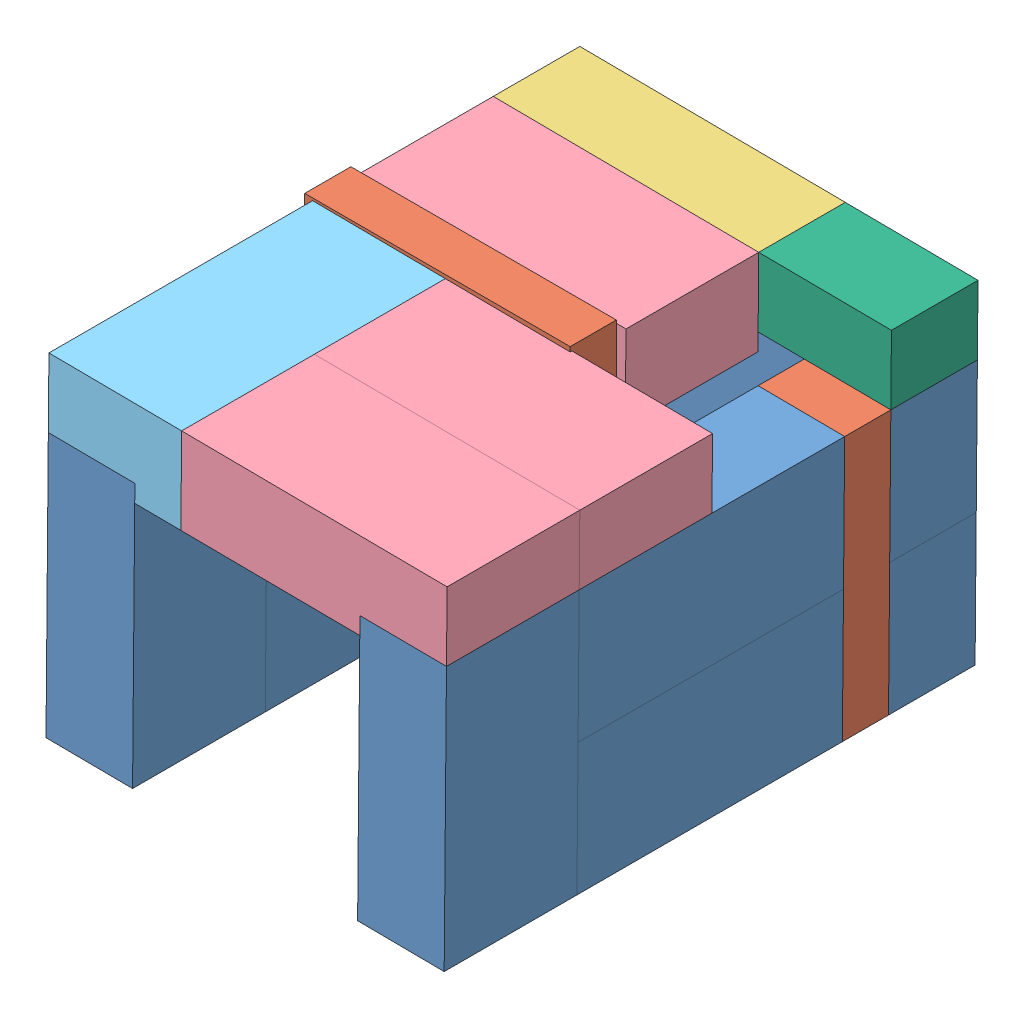
SolidWorks assembly Assem2, configuration Default. Lengths in mm.
Overall size (351.83 295.72 462.01).
21 component instances, 6 part files, 24 mates.
Components (placement in the parent):
- Side Wall ext-1: Side Wall ext [Default] at (111.7562 210.1933 441.078) size (77 230.65 385)
  - Brick-Whole-1: Brick-Whole [Default] x (-0.008727 -0.999962 0) z (0 0 1) size (230 75 115)
  - Brick-Whole-2: Brick-Whole [Default] at (0.5018 57.4978 -172.5) x (0 0 1) z (0.008727 0.999962 0) size (230 75 115)
  - Brick-Whole-3: Brick-Whole [Default] at (-0.5018 -57.4978 -172.5) x (0 0 1) z (0.008727 0.999962 0) size (230 75 115)
  - Brick-Whole-trimmed-1: Brick-Whole-trimmed [Default] at (0 0 -307.5) x (-0.008727 -0.999962 0) z (0 0 1) size (230 75 40)
- Side Wall ext-2: Side Wall ext [Default] at (381.7459 207.8371 441.078) size (77 230.65 385)
  - Brick-Whole-1: Brick-Whole [Default] x (-0.008727 -0.999962 0) z (0 0 1) size (230 75 115)
  - Brick-Whole-2: Brick-Whole [Default] at (0.5018 57.4978 -172.5) x (0 0 1) z (0.008727 0.999962 0) size (230 75 115)
  - Brick-Whole-3: Brick-Whole [Default] at (-0.5018 -57.4978 -172.5) x (0 0 1) z (0.008727 0.999962 0) size (230 75 115)
  - Brick-Whole-trimmed-1: Brick-Whole-trimmed [Default] at (0 0 -307.5) x (-0.008727 -0.999962 0) z (0 0 1) size (230 75 40)
- Side Wall-1: Side Wall [Default] at (131.7554 210.0187 76.078) x (0.000076 0.008726 0.999962) z (-0.999962 0.008727 0) size (77 230.65 345)
  - Brick-Whole-1: Brick-Whole [Default] x (-0.008727 -0.999962 0) z (0 0 1) size (230 75 115)
  - Brick-Whole-2: Brick-Whole [Default] at (0.5018 57.4978 -172.5) x (0 0 1) z (0.008727 0.999962 0) size (230 75 115)
  - Brick-Whole-3: Brick-Whole [Default] at (-0.5018 -57.4978 -172.5) x (0 0 1) z (0.008727 0.999962 0) size (230 75 115)
- Brick-Whole-70-1: Brick-Whole-70 [Default] at (190.5186 354.5114 76.078) x (0.999962 -0.008727 0) z (-0.008727 -0.999962 0) size (230 75 60)
- Brick-Sharp-BackCut-1: Brick-Sharp-BackCut [Default] at (305.4487 346.0082 441.078) x (-0.999962 0.008727 0) z (0 0 1) size (230 75 115)
- Brick-Sharp-SideCut-1: Brick-Sharp-SideCut [Default] at (132.9553 347.5135 383.578) x (0 0 1) z (0.999962 -0.008727 0) size (230 75 115)
- Brick-Sharp-BackCut-2: Brick-Sharp-BackCut [Default] at (305.4487 346.0082 326.078) x (-0.999962 0.008727 0) z (0 0 1) size (230 75 115)
- Brick-Whole-trimmed-3: Brick-Whole-trimmed [Default] at (183.9442 350.0777 250.0949) size (230 75 40)
- Brick-Sharp-BackCut-3: Brick-Sharp-BackCut [Default] at (190.4531 347.0117 171.078) x (0.999962 -0.008727 0) z (0 0 -1) size (230 75 115)
- Brick-Whole-70115-1: Brick-Whole-70115 [Default] at (363.012 353.0061 76.078) x (0.008727 0.999962 0) z (-0.999962 0.008727 0) size (60 75 115)
Mates (geometry in assembly coordinates):
- Coincident21: coincident anti-aligned: plane of Side Wall ext-1/Brick-Whole-trimmed-1 through (150.2583 324.8616 113.578) normal (0 0 -1); plane of Side Wall-1/Brick-Whole-1 through (131.7554 210.0187 113.578) normal (0 0 1)
- Coincident22: coincident aligned: plane of Side Wall ext-1/Brick-Whole-trimmed-1 through (74.2576 210.5205 133.578) normal (-0.999962 0.008727 0); plane of Side Wall-1/Brick-Whole-1 through (75.2611 325.5161 113.578) normal (-0.999962 0.008727 0)
- Coincident23: coincident aligned: plane of Side Wall ext-1/Brick-Whole-trimmed-1 through (148.2512 94.8704 113.578) normal (-0.008727 -0.999962 0); plane of Side Wall-1/Brick-Whole-1 through (188.2497 94.5213 113.578) normal (-0.008727 -0.999962 0)
- Coincident24: coincident anti-aligned: plane of Side Wall ext-2/Brick-Whole-trimmed-1 through (420.248 322.5055 113.578) normal (0 0 -1); plane of Side Wall-1/Brick-Whole-2 through (304.7506 266.0112 113.578) normal (0 0 1)
- Coincident25: coincident aligned: plane of Side Wall ext-2/Brick-Whole-trimmed-1 through (419.2445 207.5099 133.578) normal (0.999962 -0.008727 0); plane of Side Wall-1/Brick-Whole-2 through (419.2445 207.5099 113.578) normal (0.999962 -0.008727 0)
- Coincident26: coincident aligned: plane of Side Wall ext-2/Brick-Whole-trimmed-1 through (420.248 322.5055 113.578) normal (0.008727 0.999962 0); plane of Side Wall-1/Brick-Whole-2 through (420.248 322.5055 113.578) normal (0.008727 0.999962 0)
- Coincident36: coincident anti-aligned: plane of Side Wall ext-2/Brick-Whole-1 through (420.248 322.5055 383.578) normal (0.008727 0.999962 0); plane of Brick-Sharp-BackCut-1 through (305.2524 323.509 441.078) normal (-0.008727 -0.999962 0)
- Coincident37: coincident aligned: plane of Side Wall ext-2/Brick-Whole-1 through (419.2445 207.5099 441.078) normal (0.999962 -0.008727 0); plane of Brick-Sharp-BackCut-1 through (420.1171 307.506 383.578) normal (0.999962 -0.008727 0)
- Coincident38: coincident aligned: plane of Side Wall ext-2/Brick-Whole-1 through (420.248 322.5055 498.578) normal (0 0 1); plane of Brick-Sharp-BackCut-1 through (420.1171 307.506 498.578) normal (0 0 1)
- Coincident39: coincident anti-aligned: plane of Side Wall ext-2/Brick-Whole-2 through (420.248 322.5055 153.578) normal (0.008727 0.999962 0); plane of Brick-Sharp-BackCut-2 through (305.2524 323.509 326.078) normal (-0.008727 -0.999962 0)
- Coincident40: coincident aligned: plane of Side Wall ext-2/Brick-Whole-2 through (419.7462 265.0077 268.578) normal (0.999962 -0.008727 0); plane of Brick-Sharp-BackCut-2 through (420.1171 307.506 268.578) normal (0.999962 -0.008727 0)
- Coincident41: coincident anti-aligned: plane of Brick-Sharp-BackCut-1 through (420.1171 307.506 383.578) normal (0 0 -1); plane of Brick-Sharp-BackCut-2 through (420.1171 307.506 383.578) normal (0 0 1)
- Coincident42: coincident anti-aligned: plane of Side Wall ext-1/Brick-Whole-1 through (150.2583 324.8616 383.578) normal (0.008727 0.999962 0); plane of Brick-Sharp-SideCut-1 through (132.759 325.0144 383.578) normal (-0.008727 -0.999962 0)
- Coincident43: coincident anti-aligned: plane of Brick-Sharp-SideCut-1 through (190.1259 309.5131 268.578) normal (0.999962 -0.008727 0); plane of Brick-Sharp-BackCut-2 through (190.1259 309.5131 268.578) normal (-0.999962 0.008727 0)
- Coincident44: coincident aligned: plane of Brick-Sharp-BackCut-1 through (420.1171 307.506 498.578) normal (0 0 1); plane of Brick-Sharp-SideCut-1 through (75.1302 310.5167 498.578) normal (0 0 1)
- Coincident45: coincident anti-aligned: plane of Side Wall ext-1/Brick-Whole-2 through (150.2583 324.8616 153.578) normal (0.008727 0.999962 0); plane of Brick-Sharp-BackCut-3 through (190.2568 324.5126 171.078) normal (-0.008727 -0.999962 0)
- Coincident46: coincident aligned: plane of Side Wall ext-1/Brick-Whole-2 through (74.7594 268.0183 268.578) normal (-0.999962 0.008727 0); plane of Brick-Sharp-BackCut-3 through (75.1302 310.5167 228.578) normal (-0.999962 0.008727 0)
- Coincident47: coincident anti-aligned: line of Side Wall-1/Brick-Whole-1 through (75.2611 325.5161 113.578) axis (-0.008727 -0.999962 0); line of Brick-Sharp-BackCut-3 through (75.2611 325.5161 113.578) axis (0.008727 0.999962 0)
- Coincident48: coincident anti-aligned: plane of Side Wall-1/Brick-Whole-1 through (190.2568 324.5126 113.578) normal (0.008727 0.999962 0); plane of Brick-Whole-70-1 through (75.2611 325.5161 113.578) normal (-0.008727 -0.999962 0)
- Coincident49: coincident aligned: plane of Side Wall-1/Brick-Whole-1 through (131.7554 210.0187 38.578) normal (0 0 -1); plane of Brick-Whole-70-1 through (190.5186 354.5114 38.578) normal (0 0 -1)
- Coincident50: coincident aligned: plane of Side Wall-1/Brick-Whole-1 through (75.2611 325.5161 113.578) normal (-0.999962 0.008727 0); plane of Brick-Whole-70-1 through (75.7847 385.5138 113.578) normal (-0.999962 0.008727 0)
- Coincident51: coincident anti-aligned: plane of Brick-Whole-70-1 through (305.776 383.5067 113.578) normal (0.999962 -0.008727 0); plane of Brick-Whole-70115-1 through (305.2524 323.509 38.578) normal (-0.999962 0.008727 0)
- Coincident52: coincident anti-aligned: plane of Side Wall-1/Brick-Whole-2 through (420.248 322.5055 113.578) normal (0.008727 0.999962 0); plane of Brick-Whole-70115-1 through (420.248 322.5055 38.578) normal (-0.008727 -0.999962 0)
- Coincident53: coincident aligned: plane of Side Wall-1/Brick-Whole-2 through (304.7506 266.0112 38.578) normal (0 0 -1); plane of Brick-Whole-70115-1 through (363.012 353.0061 38.578) normal (0 0 -1)
